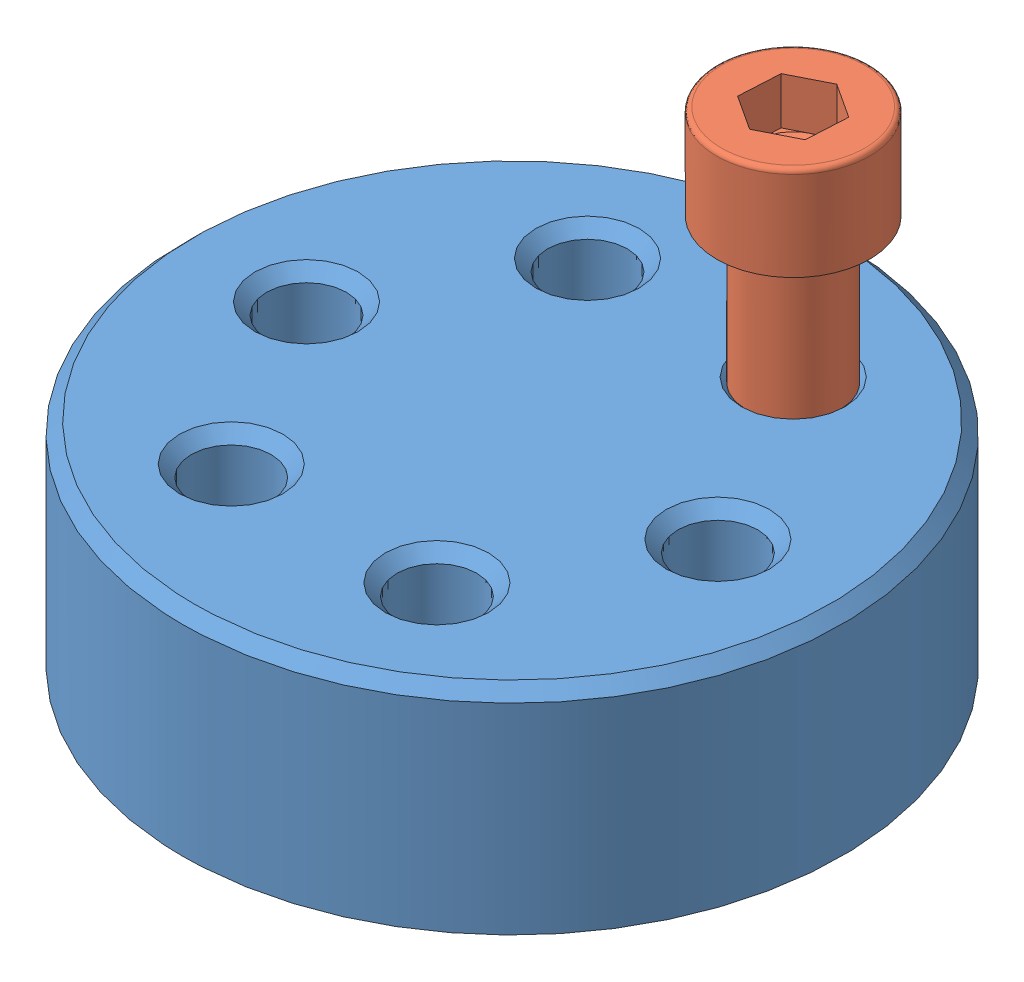
SolidWorks assembly mounting_bracket, configuration Default. Lengths in mm.
Overall size (56.1 38 56.1).
2 component instances, 2 part files, 2 mates.
Components (placement in the parent):
- mounting_bracket-1: mounting_bracket [Default] at (13.3856 17.2515 49.0758) size (56.1 18.08 56.1)
- socket head cap screw_iso-1: socket head cap screw_iso [ISO 4762 M8 x 30 - 30N] at (22.1356 55.2515 33.9204) x (0 -1 0) z (-0.546944 0 0.837169) size (38 13 13)
Mates (geometry in assembly coordinates):
- Coincident1: coincident: plane of mounting_bracket-1 through (13.3856 17.2515 49.0758) normal (0 -1 0); plane of socket head cap screw_iso-1 through (24.9062 17.2515 35.7305) normal (0 -1 0)
- Concentric1: concentric aligned: cylinder of mounting_bracket-1 through (22.1356 17.2515 33.9204) axis (0 1 0) radius 3.4; cylinder of socket head cap screw_iso-1 through (22.1356 87.0015 33.9204) axis (0 1 0) radius 4
